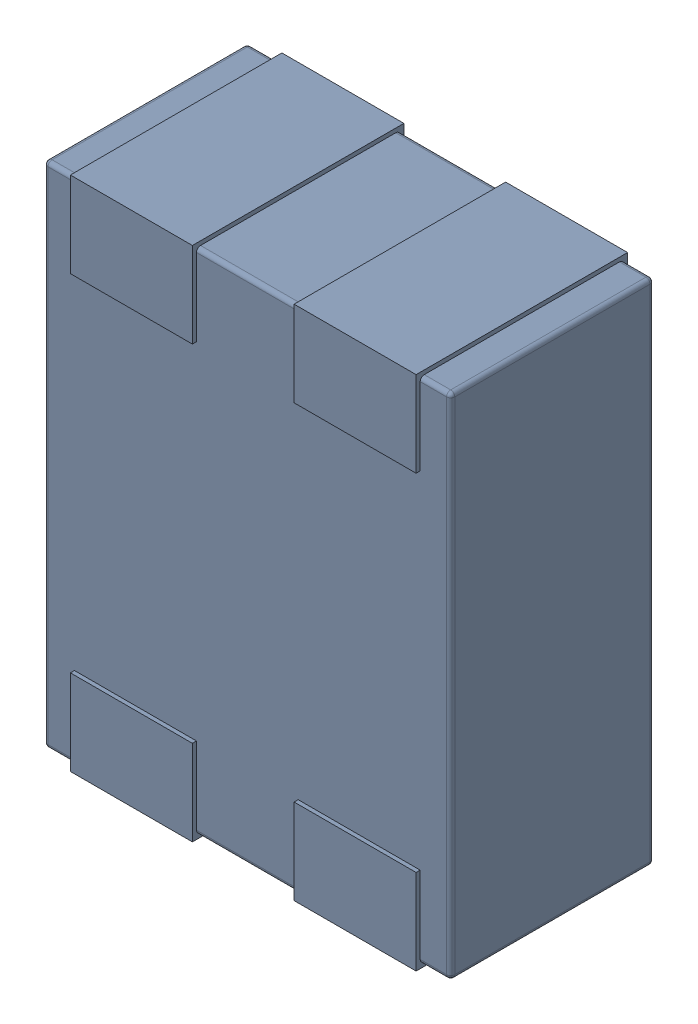
SolidWorks assembly L3, configuration Défaut. Lengths in mm.
Overall size (1 1.27 0.52).
4 component instances, 1 part files, 0 mates.
Components (placement in the parent):
- MCZ1210DH900L2TA0G-1: MCZ1210DH900L2TA0G [Défaut] at (63.1576 -33.8195 -1.6) x (-1 0 0) z (0 0 1) size (1 1.27 0.52)
  - 3D_PCB1_2021-12-30 (1).step-1: 3D_PCB1_2021-12-30 (1).step [Défaut] at origin size (1 1.27 0.52)
    - a3ec64f90eb5404ebd79eca0046a794a.step-1: a3ec64f90eb5404ebd79eca0046a794a.step [Défaut] at (5.0419 -6.8961 1.6) size (1 1.27 0.52)
      - SOLID.step_650-1: SOLID.step_650 [Défaut] at origin size (1 1.27 0.52)
